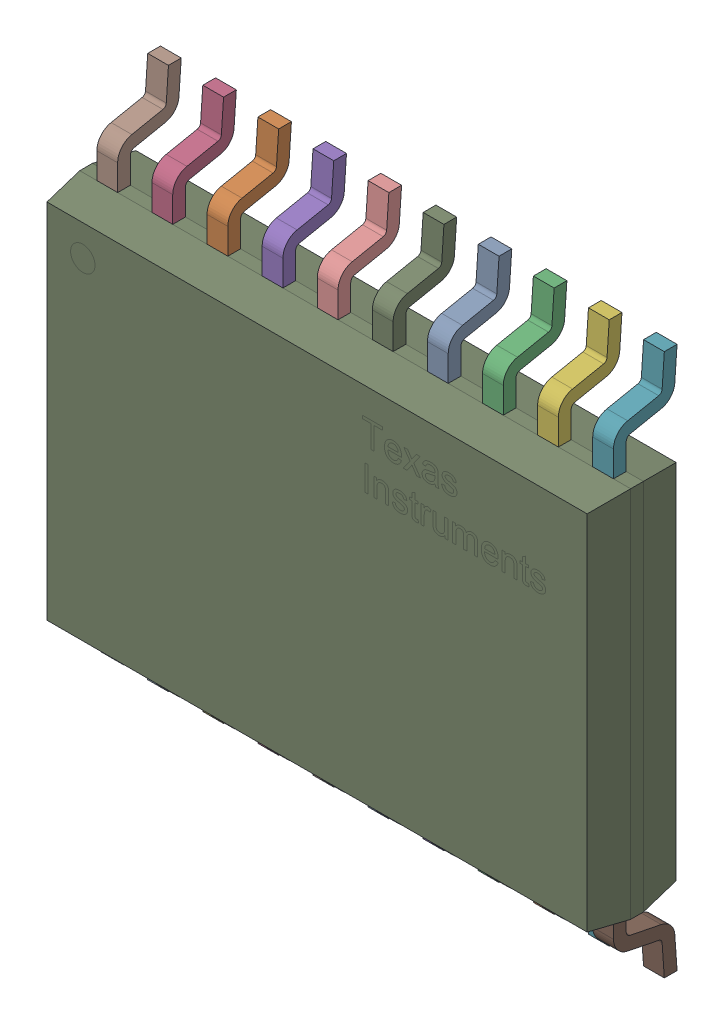
SolidWorks assembly Copy of IC_Texas_Instruments_TXS0108EQPWRQ1_eec^Copy of U2_PMPi-PCB, configuration Default. Lengths in mm.
Overall size (6.5 6.4 1.2).
21 component instances, 3 part files, 0 mates.
Components (placement in the parent):
- Copy of Texas Instruments TXS0108EQPWRQ1 2_MIR^Copy of IC_Texas_Instruments_TXS0108EQPWRQ1_eec_Copy of U2_PMPi-PCB-1: Copy of Texas Instruments TXS0108EQPWRQ1 2_MIR^Copy of IC_Texas_Instruments_TXS0108EQPWRQ1_eec_Copy of U2_PMPi-PCB [Default] at (2.2755 -1.1345 -0.3924) x (0 -1 0) z (-1 0 0) size (1 0.75 0.24)
- Copy of Texas Instruments TXS0108EQPWRQ1 2_MIR^Copy of IC_Texas_Instruments_TXS0108EQPWRQ1_eec_Copy of U2_PMPi-PCB-2: Copy of Texas Instruments TXS0108EQPWRQ1 2_MIR^Copy of IC_Texas_Instruments_TXS0108EQPWRQ1_eec_Copy of U2_PMPi-PCB [Default] at (-0.3245 -1.1345 -0.3924) x (0 -1 0) z (-1 0 0) size (1 0.75 0.24)
- Copy of Texas Instruments TXS0108EQPWRQ1 2_MIR^Copy of IC_Texas_Instruments_TXS0108EQPWRQ1_eec_Copy of U2_PMPi-PCB-3: Copy of Texas Instruments TXS0108EQPWRQ1 2_MIR^Copy of IC_Texas_Instruments_TXS0108EQPWRQ1_eec_Copy of U2_PMPi-PCB [Default] at (2.9255 -1.1345 -0.3924) x (0 -1 0) z (-1 0 0) size (1 0.75 0.24)
- Copy of Texas Instruments TXS0108EQPWRQ1 2_MIR^Copy of IC_Texas_Instruments_TXS0108EQPWRQ1_eec_Copy of U2_PMPi-PCB-4: Copy of Texas Instruments TXS0108EQPWRQ1 2_MIR^Copy of IC_Texas_Instruments_TXS0108EQPWRQ1_eec_Copy of U2_PMPi-PCB [Default] at (-0.9745 -1.1345 -0.3924) x (0 -1 0) z (-1 0 0) size (1 0.75 0.24)
- Copy of Texas Instruments TXS0108EQPWRQ1 2_MIR^Copy of IC_Texas_Instruments_TXS0108EQPWRQ1_eec_Copy of U2_PMPi-PCB-5: Copy of Texas Instruments TXS0108EQPWRQ1 2_MIR^Copy of IC_Texas_Instruments_TXS0108EQPWRQ1_eec_Copy of U2_PMPi-PCB [Default] at (0.3255 -1.1345 -0.3924) x (0 -1 0) z (-1 0 0) size (1 0.75 0.24)
- Copy of Texas Instruments TXS0108EQPWRQ1 2_MIR^Copy of IC_Texas_Instruments_TXS0108EQPWRQ1_eec_Copy of U2_PMPi-PCB-6: Copy of Texas Instruments TXS0108EQPWRQ1 2_MIR^Copy of IC_Texas_Instruments_TXS0108EQPWRQ1_eec_Copy of U2_PMPi-PCB [Default] at (3.5755 -1.1345 -0.3924) x (0 -1 0) z (-1 0 0) size (1 0.75 0.24)
- Copy of Texas Instruments TXS0108EQPWRQ1 2_MIR^Copy of IC_Texas_Instruments_TXS0108EQPWRQ1_eec_Copy of U2_PMPi-PCB-7: Copy of Texas Instruments TXS0108EQPWRQ1 2_MIR^Copy of IC_Texas_Instruments_TXS0108EQPWRQ1_eec_Copy of U2_PMPi-PCB [Default] at (4.2255 -1.1345 -0.3924) x (0 -1 0) z (-1 0 0) size (1 0.75 0.24)
- Copy of Texas Instruments TXS0108EQPWRQ1 2_MIR^Copy of IC_Texas_Instruments_TXS0108EQPWRQ1_eec_Copy of U2_PMPi-PCB-8: Copy of Texas Instruments TXS0108EQPWRQ1 2_MIR^Copy of IC_Texas_Instruments_TXS0108EQPWRQ1_eec_Copy of U2_PMPi-PCB [Default] at (-1.6245 -1.1345 -0.3924) x (0 -1 0) z (-1 0 0) size (1 0.75 0.24)
- Copy of Texas Instruments TXS0108EQPWRQ1 2_MIR^Copy of IC_Texas_Instruments_TXS0108EQPWRQ1_eec_Copy of U2_PMPi-PCB-9: Copy of Texas Instruments TXS0108EQPWRQ1 2_MIR^Copy of IC_Texas_Instruments_TXS0108EQPWRQ1_eec_Copy of U2_PMPi-PCB [Default] at (1.6255 -1.1345 -0.3924) x (0 -1 0) z (-1 0 0) size (1 0.75 0.24)
- Copy of Texas Instruments TXS0108EQPWRQ1 2_MIR^Copy of IC_Texas_Instruments_TXS0108EQPWRQ1_eec_Copy of U2_PMPi-PCB-10: Copy of Texas Instruments TXS0108EQPWRQ1 2_MIR^Copy of IC_Texas_Instruments_TXS0108EQPWRQ1_eec_Copy of U2_PMPi-PCB [Default] at (0.9755 -1.1345 -0.3924) x (0 -1 0) z (-1 0 0) size (1 0.75 0.24)
- Copy of Texas Instruments TXS0108EQPWRQ1 2^Copy of IC_Texas_Instruments_TXS0108EQPWRQ1_eec_Copy of U2_PMPi-PCB-1: Copy of Texas Instruments TXS0108EQPWRQ1 2^Copy of IC_Texas_Instruments_TXS0108EQPWRQ1_eec_Copy of U2_PMPi-PCB [Default] at (4.2255 -6.5345 -0.3924) x (0 1 0) z (1 0 0) size (1 0.75 0.24)
- Copy of Texas Instruments TXS0108EQPWRQ1 2^Copy of IC_Texas_Instruments_TXS0108EQPWRQ1_eec_Copy of U2_PMPi-PCB-2: Copy of Texas Instruments TXS0108EQPWRQ1 2^Copy of IC_Texas_Instruments_TXS0108EQPWRQ1_eec_Copy of U2_PMPi-PCB [Default] at (-1.6245 -6.5345 -0.3924) x (0 1 0) z (1 0 0) size (1 0.75 0.24)
- Copy of Texas Instruments TXS0108EQPWRQ1 2^Copy of IC_Texas_Instruments_TXS0108EQPWRQ1_eec_Copy of U2_PMPi-PCB-3: Copy of Texas Instruments TXS0108EQPWRQ1 2^Copy of IC_Texas_Instruments_TXS0108EQPWRQ1_eec_Copy of U2_PMPi-PCB [Default] at (0.9755 -6.5345 -0.3924) x (0 1 0) z (1 0 0) size (1 0.75 0.24)
- Copy of Texas Instruments TXS0108EQPWRQ1 2^Copy of IC_Texas_Instruments_TXS0108EQPWRQ1_eec_Copy of U2_PMPi-PCB-4: Copy of Texas Instruments TXS0108EQPWRQ1 2^Copy of IC_Texas_Instruments_TXS0108EQPWRQ1_eec_Copy of U2_PMPi-PCB [Default] at (2.9255 -6.5345 -0.3924) x (0 1 0) z (1 0 0) size (1 0.75 0.24)
- Copy of Texas Instruments TXS0108EQPWRQ1 2^Copy of IC_Texas_Instruments_TXS0108EQPWRQ1_eec_Copy of U2_PMPi-PCB-5: Copy of Texas Instruments TXS0108EQPWRQ1 2^Copy of IC_Texas_Instruments_TXS0108EQPWRQ1_eec_Copy of U2_PMPi-PCB [Default] at (2.2755 -6.5345 -0.3924) x (0 1 0) z (1 0 0) size (1 0.75 0.24)
- Copy of Texas Instruments TXS0108EQPWRQ1 2^Copy of IC_Texas_Instruments_TXS0108EQPWRQ1_eec_Copy of U2_PMPi-PCB-6: Copy of Texas Instruments TXS0108EQPWRQ1 2^Copy of IC_Texas_Instruments_TXS0108EQPWRQ1_eec_Copy of U2_PMPi-PCB [Default] at (-0.3245 -6.5345 -0.3924) x (0 1 0) z (1 0 0) size (1 0.75 0.24)
- Copy of Texas Instruments TXS0108EQPWRQ1 2^Copy of IC_Texas_Instruments_TXS0108EQPWRQ1_eec_Copy of U2_PMPi-PCB-7: Copy of Texas Instruments TXS0108EQPWRQ1 2^Copy of IC_Texas_Instruments_TXS0108EQPWRQ1_eec_Copy of U2_PMPi-PCB [Default] at (1.6255 -6.5345 -0.3924) x (0 1 0) z (1 0 0) size (1 0.75 0.24)
- Copy of Texas Instruments TXS0108EQPWRQ1 2^Copy of IC_Texas_Instruments_TXS0108EQPWRQ1_eec_Copy of U2_PMPi-PCB-8: Copy of Texas Instruments TXS0108EQPWRQ1 2^Copy of IC_Texas_Instruments_TXS0108EQPWRQ1_eec_Copy of U2_PMPi-PCB [Default] at (-0.9745 -6.5345 -0.3924) x (0 1 0) z (1 0 0) size (1 0.75 0.24)
- Copy of Texas Instruments TXS0108EQPWRQ1 2^Copy of IC_Texas_Instruments_TXS0108EQPWRQ1_eec_Copy of U2_PMPi-PCB-9: Copy of Texas Instruments TXS0108EQPWRQ1 2^Copy of IC_Texas_Instruments_TXS0108EQPWRQ1_eec_Copy of U2_PMPi-PCB [Default] at (3.5755 -6.5345 -0.3924) x (0 1 0) z (1 0 0) size (1 0.75 0.24)
- Copy of Texas Instruments TXS0108EQPWRQ1 2^Copy of IC_Texas_Instruments_TXS0108EQPWRQ1_eec_Copy of U2_PMPi-PCB-10: Copy of Texas Instruments TXS0108EQPWRQ1 2^Copy of IC_Texas_Instruments_TXS0108EQPWRQ1_eec_Copy of U2_PMPi-PCB [Default] at (0.3255 -6.5345 -0.3924) x (0 1 0) z (1 0 0) size (1 0.75 0.24)
- Copy of Texas Instruments TXS0108EQPWRQ1 1^Copy of IC_Texas_Instruments_TXS0108EQPWRQ1_eec_Copy of U2_PMPi-PCB-1: Copy of Texas Instruments TXS0108EQPWRQ1 1^Copy of IC_Texas_Instruments_TXS0108EQPWRQ1_eec_Copy of U2_PMPi-PCB [Default] at (1.423 -3.8345 -0.6174) size (6.5 4.4 1.05)
